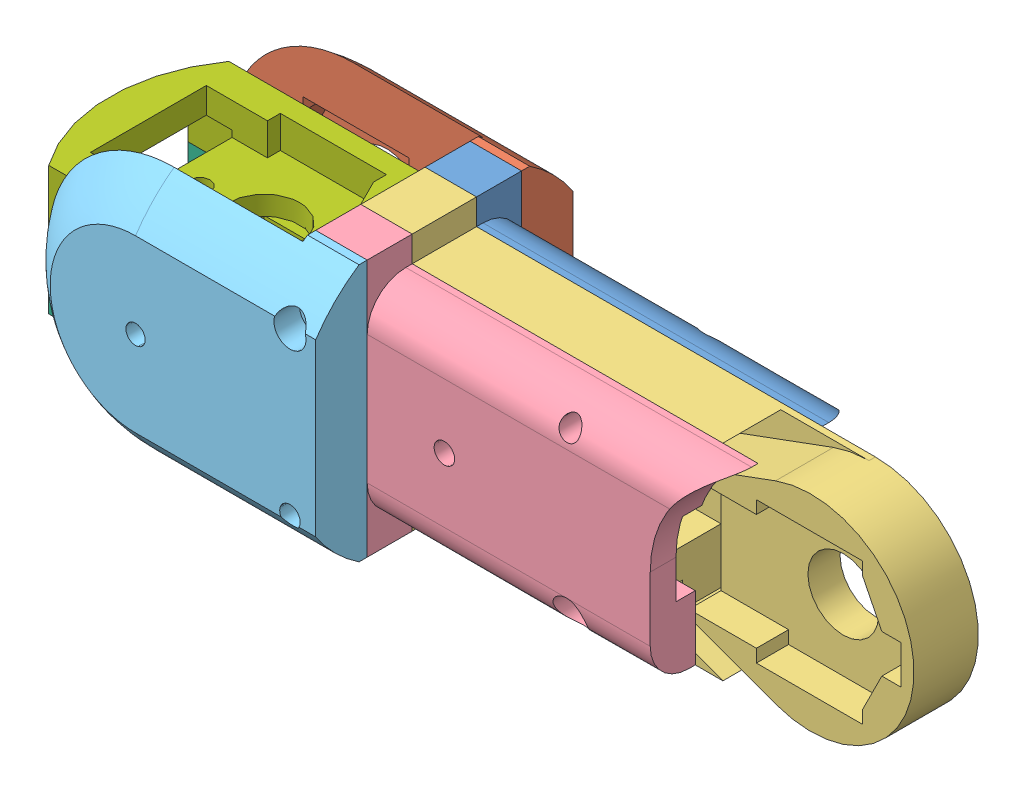
SolidWorks assembly fingerP-assembly, configuration Default. Lengths in mm.
Overall size (65 20 20.25).
7 component instances, 7 part files, 17 mates.
Components (placement in the parent):
- fingerP-left-2: fingerP-left [Default] at (8.5129 15.1032 -35.3025) size (31.19 20 3.5)
- fingerP-left2-2: fingerP-left2 [Default] at (8.6741 15.1032 -39.3025) size (23.75 20 4.12)
- fingerP-middle-2: fingerP-middle [Default] at (-18.6135 15.1032 -31.8025) size (43 20 5)
- fingerP-right-2: fingerP-right [Default] at (8.5129 15.1032 -26.8025) size (31.19 20 3.5)
- fingerP-right2-2: fingerP-right2 [Default] at (8.6741 15.1032 -19.3025) size (23.75 20 5.12)
- fingerP-joint1-1: fingerP-joint1 [Default] at (-3.3259 20.1032 -37.3025) x (1 0 0) z (0 0 -1) size (21 5 14)
- fingerP-joint2-1: fingerP-joint2 [Default] at (-3.3259 20.1032 -37.3025) x (1 0 0) z (0 0 -1) size (21 5 14)
Mates (geometry in assembly coordinates):
- Concentric1: concentric aligned: cylinder of fingerP-left-2 through (20.6741 21.3532 -14.9385) axis (0 0 -1) radius 0.8; cylinder of fingerP-middle-2 through (20.6741 21.3532 -9.9385) axis (0 0 -1) radius 0.8
- Concentric2: concentric aligned: cylinder of fingerP-left-2 through (20.6741 8.8532 -14.9385) axis (0 0 -1) radius 0.8; cylinder of fingerP-middle-2 through (20.6741 8.8532 -9.9385) axis (0 0 -1) radius 0.8
- Coincident1: coincident anti-aligned: plane of fingerP-left-2 through (8.5129 15.1032 -14.9385) normal (0 0 1); plane of fingerP-middle-2 through (-18.6135 15.1032 -14.9385) normal (0 0 -1)
- Concentric3: concentric aligned: cylinder of fingerP-middle-2 through (20.6741 21.3532 -9.9385) axis (0 0 -1) radius 0.8; cylinder of fingerP-right-2 through (20.6741 21.3532 -6.4385) axis (0 0 -1) radius 0.8
- Concentric4: concentric aligned: cylinder of fingerP-middle-2 through (20.6741 8.8532 -9.9385) axis (0 0 -1) radius 0.8; cylinder of fingerP-right-2 through (20.6741 8.8532 -6.4385) axis (0 0 -1) radius 0.8
- Coincident2: coincident anti-aligned: plane of fingerP-middle-2 through (-18.6135 15.1032 -9.9385) normal (0 0 1); plane of fingerP-right-2 through (8.5129 15.1032 -9.9385) normal (0 0 -1)
- Concentric5: concentric aligned: cylinder of fingerP-left-2 through (20.6741 21.3532 -14.9385) axis (0 0 -1) radius 0.8; cylinder of fingerP-left2-2 through (20.6741 21.3532 -18.4385) axis (0 0 -1) radius 0.8
- Concentric6: concentric aligned: cylinder of fingerP-left-2 through (20.6741 8.8532 -14.9385) axis (0 0 -1) radius 0.8; cylinder of fingerP-left2-2 through (20.6741 8.8532 -18.4385) axis (0 0 -1) radius 0.8
- Coincident3: coincident anti-aligned: plane of fingerP-left-2 through (8.5129 15.1032 -18.4385) normal (0 0 -1); plane of fingerP-left2-2 through (8.6741 15.1032 -18.4385) normal (0 0 1)
- Concentric7: concentric anti-aligned: cylinder of fingerP-right-2 through (20.6741 21.3532 -6.4385) axis (0 0 -1) radius 0.8; cylinder of fingerP-right2-2 through (20.6741 21.3532 -7.4385) axis (0 0 1) radius 0.8
- Concentric8: concentric anti-aligned: cylinder of fingerP-right-2 through (20.6741 8.8532 -6.4385) axis (0 0 -1) radius 0.8; cylinder of fingerP-right2-2 through (20.6741 8.8532 -7.4385) axis (0 0 1) radius 0.8
- Coincident4: coincident anti-aligned: plane of fingerP-right-2 through (8.5129 15.1032 -6.4385) normal (0 0 1); plane of fingerP-right2-2 through (8.6741 15.1032 -6.4385) normal (0 0 -1)
- Concentric9: concentric aligned: cylinder of fingerP-joint1-1 through (13.6741 18.1032 -29.3025) axis (0 -1 0) radius 0.8; cylinder of fingerP-joint2-1 through (13.6741 18.1032 -29.3025) axis (0 -1 0) radius 0.8
- Concentric10: concentric aligned: cylinder of fingerP-joint1-1 through (3.6741 18.1032 -29.3025) axis (0 -1 0) radius 0.8; cylinder of fingerP-joint2-1 through (3.6741 18.1032 -29.3025) axis (0 -1 0) radius 0.8
- Coincident5: coincident anti-aligned: plane of fingerP-joint1-1 through (-3.3259 15.1032 -37.3025) normal (0 1 0); plane of fingerP-joint2-1 through (-3.3259 15.1032 -37.3025) normal (0 -1 0)
- Concentric11: concentric aligned: cylinder of fingerP-right2-2 through (8.6741 15.1032 -7.4385) axis (0 0 1) radius 2; cylinder of fingerP-joint1-1 through (8.6741 15.1032 -24.3025) axis (0 0 1) radius 2.25
- Coincident6: coincident anti-aligned: plane of fingerP-right2-2 through (8.6741 15.1032 -22.3025) normal (0 0 -1); plane of fingerP-joint2-1 through (8.6741 10.1032 -22.3025) normal (0 0 1)
